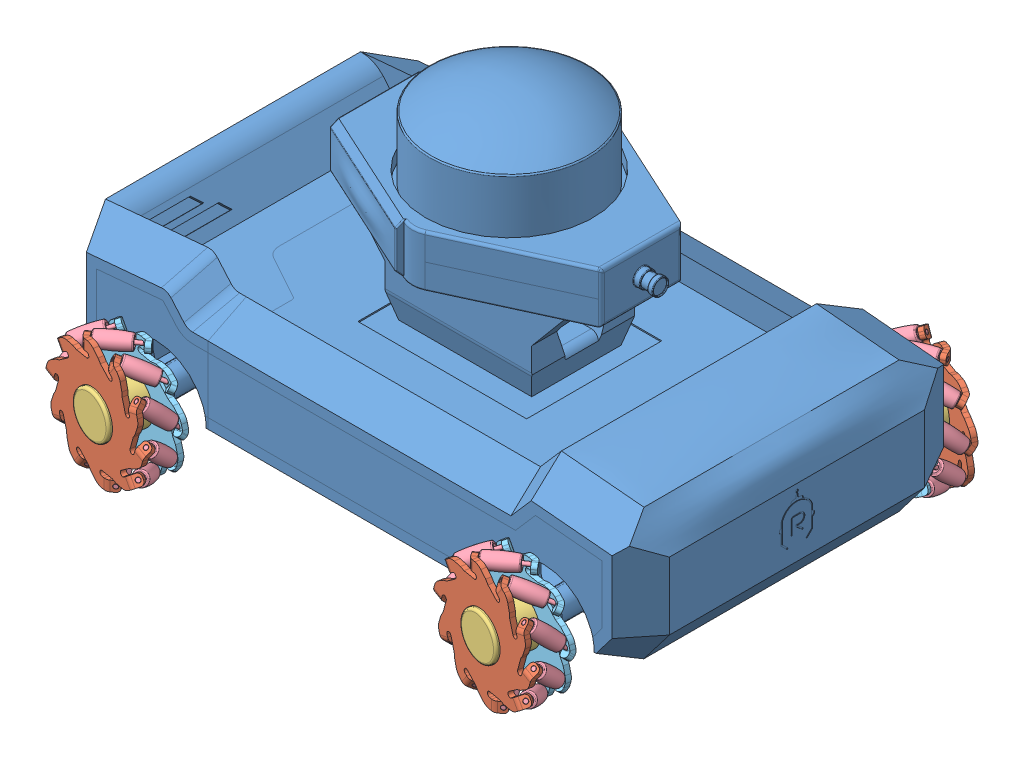
SolidWorks assembly FULL ASSEMBLY, configuration Default. Lengths in mm.
Overall size (474.58 296.12 465.37).
57 component instances, 5 part files, 12 mates.
Components (placement in the parent):
- Part2g-1: Part2g [Default] at (93.2668 203.0266 396.0208) size (445.74 239 264.43)
- Assem2-1: Assem2 [Default] at (311.6698 241.1948 460.7815) x (-0.436438 -0.421358 -0.794971) z (-0.896695 0.131144 0.422775) size (110.15 111.26 114.6)
  - 22-2: 22 [Default] at (56.0668 49.3834 58.4949) x (-0.218508 -0.897857 0.38224) z (0.707107 -0.415627 -0.572061) size (96.82 92.49 8.73)
  - 2222-1: 2222 [Default] at (56.0668 49.3834 58.4949) x (-0.567853 0.14831 -0.809659) z (0.707107 -0.415627 -0.572061) size (36 36 49)
  - 222-5: 222 [Default] at (61.9099 77.2825 25.4401) size (34 12 12)
  - 22222-3: 22222 [Default] at (72.41 39.7771 45.273) x (-0.567853 0.14831 -0.809659) z (-0.707107 0.415627 0.572061) size (95.75 91.46 7.41)
  - 222-15: 222 [Default] at (79.796 82.8195 43.5256) x (0.904508 -0.392378 0.167045) z (-0.321554 -0.370218 0.871517) size (34 12 12)
  - 222-16: 222 [Default] at (91.7096 73.7679 64.828) x (0.654508 -0.747138 0.115776) z (-0.674793 -0.508208 0.535144) size (34 12 12)
  - 222-17: 222 [Default] at (93.1002 53.5853 81.2104) x (0.345492 -0.928773 -0.134224) z (-0.924793 -0.361261 0.119364) size (34 12 12)
  - 222-18: 222 [Default] at (83.4366 29.9806 86.4153) x (0.095492 -0.867906 -0.487463) z (-0.976062 0.014492 -0.217008) size (34 12 12)
  - 222-19: 222 [Default] at (66.41 11.9702 78.4547) x (0 -0.587785 -0.809017) z (-0.809017 0.475528 -0.345492) size (34 12 12)
  - 222-20: 222 [Default] at (48.5239 6.4332 60.3691) x (0.095492 -0.195407 -0.976062) z (-0.487463 0.845746 -0.217008) size (34 12 12)
  - 222-21: 222 [Default] at (36.6103 15.4848 39.0667) x (0.345492 0.159352 -0.924793) z (-0.134224 0.983736 0.119364) size (34 12 12)
  - 222-22: 222 [Default] at (35.2197 35.6674 22.6843) x (0.654508 0.340988 -0.674793) z (0.115776 0.836789 0.535144) size (34 12 12)
  - 222-23: 222 [Default] at (44.8833 59.272 17.4794) x (0.904508 0.280121 -0.321554) z (0.167045 0.461036 0.871517) size (34 12 12)
- Assem2-2: Assem2 [Default] at (-133.7692 118.8583 435.8198) x (0.682014 0.421358 -0.597758) z (0.698021 -0.131144 0.703966) size (110.15 111.26 114.6)
  - 22-2: 22 [Default] at (56.0668 49.3834 58.4949) x (-0.218508 -0.897857 0.38224) z (0.707107 -0.415627 -0.572061) size (96.82 92.49 8.73)
  - 2222-1: 2222 [Default] at (56.0668 49.3834 58.4949) x (-0.567853 0.14831 -0.809659) z (0.707107 -0.415627 -0.572061) size (36 36 49)
  - 222-5: 222 [Default] at (61.9099 77.2825 25.4401) size (34 12 12)
  - 22222-3: 22222 [Default] at (72.41 39.7771 45.273) x (-0.567853 0.14831 -0.809659) z (-0.707107 0.415627 0.572061) size (95.75 91.46 7.41)
  - 222-15: 222 [Default] at (79.796 82.8195 43.5256) x (0.904508 -0.392378 0.167045) z (-0.321554 -0.370218 0.871517) size (34 12 12)
  - 222-16: 222 [Default] at (91.7096 73.7679 64.828) x (0.654508 -0.747138 0.115776) z (-0.674793 -0.508208 0.535144) size (34 12 12)
  - 222-17: 222 [Default] at (93.1002 53.5853 81.2104) x (0.345492 -0.928773 -0.134224) z (-0.924793 -0.361261 0.119364) size (34 12 12)
  - 222-18: 222 [Default] at (83.4366 29.9806 86.4153) x (0.095492 -0.867906 -0.487463) z (-0.976062 0.014492 -0.217008) size (34 12 12)
  - 222-19: 222 [Default] at (66.41 11.9702 78.4547) x (0 -0.587785 -0.809017) z (-0.809017 0.475528 -0.345492) size (34 12 12)
  - 222-20: 222 [Default] at (48.5239 6.4332 60.3691) x (0.095492 -0.195407 -0.976062) z (-0.487463 0.845746 -0.217008) size (34 12 12)
  - 222-21: 222 [Default] at (36.6103 15.4848 39.0667) x (0.345492 0.159352 -0.924793) z (-0.134224 0.983736 0.119364) size (34 12 12)
  - 222-22: 222 [Default] at (35.2197 35.6674 22.6843) x (0.654508 0.340988 -0.674793) z (0.115776 0.836789 0.535144) size (34 12 12)
  - 222-23: 222 [Default] at (44.8833 59.272 17.4794) x (0.904508 0.280121 -0.321554) z (0.167045 0.461036 0.871517) size (34 12 12)
- Assem2-4: Assem2 [Default] at (321.2454 118.8583 169.4449) x (-0.775452 0.421358 0.470246) z (-0.565174 -0.131144 -0.814481) size (110.15 111.26 114.6)
  - 22-2: 22 [Default] at (56.0668 49.3834 58.4949) x (-0.218508 -0.897857 0.38224) z (0.707107 -0.415627 -0.572061) size (96.82 92.49 8.73)
  - 2222-1: 2222 [Default] at (56.0668 49.3834 58.4949) x (-0.567853 0.14831 -0.809659) z (0.707107 -0.415627 -0.572061) size (36 36 49)
  - 222-5: 222 [Default] at (61.9099 77.2825 25.4401) size (34 12 12)
  - 22222-3: 22222 [Default] at (72.41 39.7771 45.273) x (-0.567853 0.14831 -0.809659) z (-0.707107 0.415627 0.572061) size (95.75 91.46 7.41)
  - 222-15: 222 [Default] at (79.796 82.8195 43.5256) x (0.904508 -0.392378 0.167045) z (-0.321554 -0.370218 0.871517) size (34 12 12)
  - 222-16: 222 [Default] at (91.7096 73.7679 64.828) x (0.654508 -0.747138 0.115776) z (-0.674793 -0.508208 0.535144) size (34 12 12)
  - 222-17: 222 [Default] at (93.1002 53.5853 81.2104) x (0.345492 -0.928773 -0.134224) z (-0.924793 -0.361261 0.119364) size (34 12 12)
  - 222-18: 222 [Default] at (83.4366 29.9806 86.4153) x (0.095492 -0.867906 -0.487463) z (-0.976062 0.014492 -0.217008) size (34 12 12)
  - 222-19: 222 [Default] at (66.41 11.9702 78.4547) x (0 -0.587785 -0.809017) z (-0.809017 0.475528 -0.345492) size (34 12 12)
  - 222-20: 222 [Default] at (48.5239 6.4332 60.3691) x (0.095492 -0.195407 -0.976062) z (-0.487463 0.845746 -0.217008) size (34 12 12)
  - 222-21: 222 [Default] at (36.6103 15.4848 39.0667) x (0.345492 0.159352 -0.924793) z (-0.134224 0.983736 0.119364) size (34 12 12)
  - 222-22: 222 [Default] at (35.2197 35.6674 22.6843) x (0.654508 0.340988 -0.674793) z (0.115776 0.836789 0.535144) size (34 12 12)
  - 222-23: 222 [Default] at (44.8833 59.272 17.4794) x (0.904508 0.280121 -0.321554) z (0.167045 0.461036 0.871517) size (34 12 12)
- Assem2-5: Assem2 [Default] at (-117.7083 241.1948 120.2799) x (0.291763 -0.421358 0.85868) z (0.956487 0.131144 -0.260642) size (110.15 111.26 114.6)
  - 22-2: 22 [Default] at (56.0668 49.3834 58.4949) x (-0.218508 -0.897857 0.38224) z (0.707107 -0.415627 -0.572061) size (96.82 92.49 8.73)
  - 2222-1: 2222 [Default] at (56.0668 49.3834 58.4949) x (-0.567853 0.14831 -0.809659) z (0.707107 -0.415627 -0.572061) size (36 36 49)
  - 222-5: 222 [Default] at (61.9099 77.2825 25.4401) size (34 12 12)
  - 22222-3: 22222 [Default] at (72.41 39.7771 45.273) x (-0.567853 0.14831 -0.809659) z (-0.707107 0.415627 0.572061) size (95.75 91.46 7.41)
  - 222-15: 222 [Default] at (79.796 82.8195 43.5256) x (0.904508 -0.392378 0.167045) z (-0.321554 -0.370218 0.871517) size (34 12 12)
  - 222-16: 222 [Default] at (91.7096 73.7679 64.828) x (0.654508 -0.747138 0.115776) z (-0.674793 -0.508208 0.535144) size (34 12 12)
  - 222-17: 222 [Default] at (93.1002 53.5853 81.2104) x (0.345492 -0.928773 -0.134224) z (-0.924793 -0.361261 0.119364) size (34 12 12)
  - 222-18: 222 [Default] at (83.4366 29.9806 86.4153) x (0.095492 -0.867906 -0.487463) z (-0.976062 0.014492 -0.217008) size (34 12 12)
  - 222-19: 222 [Default] at (66.41 11.9702 78.4547) x (0 -0.587785 -0.809017) z (-0.809017 0.475528 -0.345492) size (34 12 12)
  - 222-20: 222 [Default] at (48.5239 6.4332 60.3691) x (0.095492 -0.195407 -0.976062) z (-0.487463 0.845746 -0.217008) size (34 12 12)
  - 222-21: 222 [Default] at (36.6103 15.4848 39.0667) x (0.345492 0.159352 -0.924793) z (-0.134224 0.983736 0.119364) size (34 12 12)
  - 222-22: 222 [Default] at (35.2197 35.6674 22.6843) x (0.654508 0.340988 -0.674793) z (0.115776 0.836789 0.535144) size (34 12 12)
  - 222-23: 222 [Default] at (44.8833 59.272 17.4794) x (0.904508 0.280121 -0.321554) z (0.167045 0.461036 0.871517) size (34 12 12)
Mates (geometry in assembly coordinates):
- Concentric1: concentric aligned: circle of Part2g-1; circle of Assem2-2/2222-1
- Coincident1: coincident anti-aligned: plane of Part2g-1 through (-58.6701 187.0266 423.8208) normal (0 -1 0); plane of Assem2-2/2222-1 through (-58.6701 187.0266 423.8208) normal (0 1 0)
- Concentric2: concentric anti-aligned: circle of Part2g-1; circle of Assem2-1/2222-1
- Coincident2: coincident anti-aligned: plane of Part2g-1 through (245.2037 187.0266 423.8208) normal (0 -1 0); plane of Assem2-1/2222-1 through (245.2037 187.0266 423.8208) normal (0 1 0)
- Concentric3: concentric aligned: circle of Part2g-1; circle of Assem2-5/2222-1
- Coincident3: coincident anti-aligned: plane of Part2g-1 through (-58.6701 187.0266 168.2208) normal (0 -1 0); plane of Assem2-5/2222-1 through (-58.6701 187.0266 168.2208) normal (0 1 0)
- Concentric4: concentric anti-aligned: circle of Part2g-1; circle of Assem2-4/2222-1
- Coincident4: coincident anti-aligned: circle of Part2g-1; plane of Assem2-4/2222-1 through (245.2037 187.0266 168.2208) normal (0 1 0)
- LimitAngle11: limit planar angle = 0.174533 rad anti-aligned: plane of Assem2-4/22222-3 through (250.7059 179.126 153.1037) normal (0.34202 0 -0.939693); plane of Assem2-1/22222-3 through (242.4102 180.9271 439.6637) normal (-0.173648 0 0.984808)
- LimitAngle12: limit planar angle = 0.174533 rad aligned: plane of Part2g-1 through (93.2668 203.0266 396.0208) normal (0 0 1); plane of Assem2-1/22222-3 through (242.4102 180.9271 439.6637) normal (-0.173648 0 0.984808)
- LimitAngle13: limit planar angle = 0.174533 rad aligned: plane of Assem2-5/22222-3 through (-53.1679 180.9271 153.1037) normal (0.34202 0 -0.939693); plane of Assem2-2/22-2 through (-65.4771 179.126 462.4253) normal (0.173648 0 -0.984808)
- LimitAngle15: limit planar angle = 0.174533 rad anti-aligned: plane of Part2g-1 through (93.2668 203.0266 396.0208) normal (0 0 1); plane of Assem2-2/22-2 through (-65.4771 179.126 462.4253) normal (0.173648 0 -0.984808)
